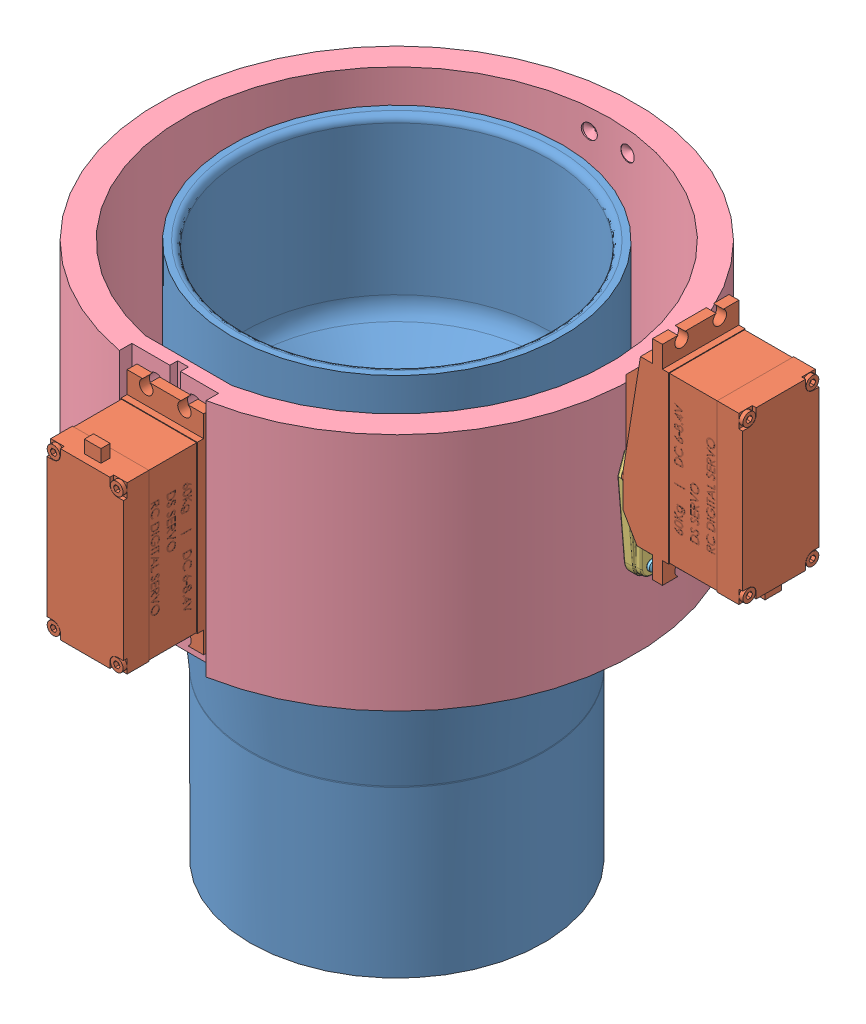
SolidWorks assembly Gimbal V7, configuration Default. Lengths in mm.
Overall size (244.08 241.79 215.67).
20 component instances, 8 part files, 37 mates.
Components (placement in the parent):
- Gimbal Nozzle - Rigid-1: Gimbal Nozzle - Rigid [Default] at origin size (130 210 130)
- Servo 1_Gimbal System_TVR_UBC Rocket-1: Servo 1_Gimbal System_TVR_UBC Rocket [Default] at (-231.9464 -144.8218 286.4196) x (0 1 0) z (0 0 -1) size (81.92 30 55.94)
  - Assem3^Servo 1_Gimbal System_TVR_UBC Rocket-1: Assem3^Servo 1_Gimbal System_TVR_UBC Rocket [Default] at origin (virtual)
  - 60Kg Servo-1: 60Kg Servo [Default] at (97.8618 231.9464 179.8846) x (-1 0 0) z (0 1 0) size (81.92 55.94 30)
- V4_Linkage_Gimbal System_TVR_UBC Rocket-1: V4_Linkage_Gimbal System_TVR_UBC Rocket [Default] at (0 -22.2131 65) x (0 -1 0) z (0 0 1) size (42.76 14.24 8)
- Servo 1_Gimbal System_TVR_UBC Rocket-2: Servo 1_Gimbal System_TVR_UBC Rocket [Default] at (314.8225 88.6957 -231.9464) x (0 -1 0) z (-1 0 0) size (81.92 30 55.94)
  - Assem3^Servo 1_Gimbal System_TVR_UBC Rocket-1: Assem3^Servo 1_Gimbal System_TVR_UBC Rocket [Default] at origin (virtual)
  - 60Kg Servo-1: 60Kg Servo [Default] at (97.8618 231.9464 179.8846) x (-1 0 0) z (0 1 0) size (81.92 55.94 30)
- Part2-1: Part2 [Default] at origin
- Part3-1: Part3 [Default] at origin
- Part4-1: Part4 [Default] x (1 0 0) z (0 1 0) size (186.81 185.25 93.92)
- V4_Linkage_Gimbal System_TVR_UBC Rocket-2: V4_Linkage_Gimbal System_TVR_UBC Rocket [Default] at (93.4029 -22.2131 0) x (0 -1 0) z (1 0 0) size (42.76 14.24 8)
- 95836A113_Black-Oxide 18-8 Stainless Steel Pan Head Phillips Screws-1: 95836A113_Black-Oxide 18-8 Stainless Steel Pan Head Phillips Screws [95836A113] at (0 -50.1169 67.33) size (4 4 11.88)
- 95836A113_Black-Oxide 18-8 Stainless Steel Pan Head Phillips Screws-2: 95836A113_Black-Oxide 18-8 Stainless Steel Pan Head Phillips Screws [95836A113] at (0 -60.1169 67.33) x (0.864816 0.502088 0) z (0 0 1) size (4 4 11.88)
- 94459A120_Heat-Set Inserts for Plastic-1: 94459A120_Heat-Set Inserts for Plastic [94459A120] at (0 -50.1169 63) x (-0.923728 -0.383049 0) z (-0.383049 0.923728 0) size (3.62 4.02 3.63)
- 94459A120_Heat-Set Inserts for Plastic-2: 94459A120_Heat-Set Inserts for Plastic [94459A120] at (0 -60.1169 63) x (-0.923835 -0.38279 0) z (-0.38279 0.923835 0) size (3.62 4.02 3.63)
- 94459A120_Heat-Set Inserts for Plastic-3: 94459A120_Heat-Set Inserts for Plastic [94459A120] at (91.4029 -50.1169 0) x (0 0.381849 -0.924225) z (0 -0.924225 -0.381849) size (3.62 4.02 3.63)
- 94459A120_Heat-Set Inserts for Plastic-4: 94459A120_Heat-Set Inserts for Plastic [94459A120] at (91.4029 -60.1169 0) x (0 0.381849 -0.924225) z (0 -0.924225 -0.381849) size (3.62 4.02 3.63)
- 95836A113_Black-Oxide 18-8 Stainless Steel Pan Head Phillips Screws-3: 95836A113_Black-Oxide 18-8 Stainless Steel Pan Head Phillips Screws [95836A113] at (95.7329 -60.1169 0) x (0 -0.924225 -0.381849) z (1 0 0) size (4 4 11.88)
- 95836A113_Black-Oxide 18-8 Stainless Steel Pan Head Phillips Screws-4: 95836A113_Black-Oxide 18-8 Stainless Steel Pan Head Phillips Screws [95836A113] at (95.7329 -50.1169 0) x (0 -0.924225 -0.381849) z (1 0 0) size (4 4 11.88)
Mates (geometry in assembly coordinates):
- Coincident3: coincident aligned: plane of Gimbal Nozzle - Rigid-1 through (0 0 0) normal (0 0 1)
- Coincident4: coincident aligned: plane of Gimbal Nozzle - Rigid-1 through (0 0 0) normal (0 1 0)
- Coincident5: coincident aligned: plane of Gimbal Nozzle - Rigid-1 through (0 0 0) normal (1 0 0)
- Coincident6: coincident aligned: plane of Servo 1_Gimbal System_TVR_UBC Rocket-2/60Kg Servo-1 through (134.9379 -9.1661 0) normal (0 0 1)
- Parallel1: parallel anti-aligned: plane of Servo 1_Gimbal System_TVR_UBC Rocket-2/60Kg Servo-1 through (134.9379 -9.1661 0) normal (-1 0 0)
- InPlace2: in place: plane of Part4-1 through (0 0 0) normal (0 1 0); moOrthogonalPlaneRef_w of Part4-1 through (0 0 0) normal (0 0 -1); plane of Part4-1 through (0 0 0) normal (1 0 0); unknown of Part4-1
- Coincident12: coincident aligned: 
- Coincident13: coincident aligned: plane of Part4-1 through (0 0 0) normal (0 0 -1)
- Coincident14: coincident anti-aligned: plane of Part4-1 through (0 0 0) normal (1 0 0)
- Coincident15: coincident aligned: plane of Servo 1_Gimbal System_TVR_UBC Rocket-1/60Kg Servo-1 through (0 -46.96 106.535) normal (1 0 0)
- Parallel2: parallel anti-aligned: plane of Gimbal Nozzle - Rigid-1 through (0 0 0) normal (0 0 1); plane of Servo 1_Gimbal System_TVR_UBC Rocket-1/60Kg Servo-1 through (0 -46.96 106.535) normal (0 0 -1)
- Distance3: distance = 6 mm aligned: plane of Servo 1_Gimbal System_TVR_UBC Rocket-1/60Kg Servo-1 through (15 -6 86.93) normal (0 1 0); plane of Part4-1 through (0 0 0) normal (0 1 0)
- Coincident23: coincident: plane of Servo 1_Gimbal System_TVR_UBC Rocket-1/60Kg Servo-1 through (0 -28.0631 106.535) normal (0 1 0); line of Servo 1_Gimbal System_TVR_UBC Rocket-2 through (98.4856 -28.0631 0) axis (-1 0 0)
- Concentric3: concentric anti-aligned: circle of Servo 1_Gimbal System_TVR_UBC Rocket-1/60Kg Servo-1; circle of V4_Linkage_Gimbal System_TVR_UBC Rocket-1
- Coincident24: coincident anti-aligned: plane of Servo 1_Gimbal System_TVR_UBC Rocket-1/60Kg Servo-1 through (0 -28.0631 67.5) normal (0 0 -1); plane of V4_Linkage_Gimbal System_TVR_UBC Rocket-1 through (0 -28.0631 67.5) normal (0 0 1)
- Parallel4: parallel aligned: plane of V4_Linkage_Gimbal System_TVR_UBC Rocket-1 through (0 -22.2131 65) normal (1 0 0)
- Tangent1: tangent anti-aligned: cylinder of Gimbal Nozzle - Rigid-1 through (0 0 0) axis (0 1 0) radius 65; plane of V4_Linkage_Gimbal System_TVR_UBC Rocket-1 through (0.5 -28.0631 65) normal (0 0 -1)
- Concentric4: concentric aligned: circle of Servo 1_Gimbal System_TVR_UBC Rocket-2/60Kg Servo-1; circle of V4_Linkage_Gimbal System_TVR_UBC Rocket-2
- Coincident25: coincident anti-aligned: plane of Servo 1_Gimbal System_TVR_UBC Rocket-2/60Kg Servo-1 through (95.9029 -28.0631 0) normal (-1 0 0); plane of V4_Linkage_Gimbal System_TVR_UBC Rocket-2 through (95.9029 -28.0631 0) normal (1 0 0)
- Perpendicular1: perpendicular: plane of V4_Linkage_Gimbal System_TVR_UBC Rocket-2 through (93.4029 -22.2131 0) normal (0 0 -1)
- Tangent2: tangent anti-aligned: cylinder of Part4-1 through (0 -364.1034 0) axis (0 1 0) radius 93.4029; plane of V4_Linkage_Gimbal System_TVR_UBC Rocket-2 through (93.4029 -28.0631 -0.5) normal (-1 0 0)
- Concentric5: concentric aligned: circle of V4_Linkage_Gimbal System_TVR_UBC Rocket-1; circle of 95836A113_Black-Oxide 18-8 Stainless Steel Pan Head Phillips Screws-1
- Coincident30: coincident anti-aligned: plane of V4_Linkage_Gimbal System_TVR_UBC Rocket-1 through (0 -28.0631 71.47) normal (0 0 1); plane of 95836A113_Black-Oxide 18-8 Stainless Steel Pan Head Phillips Screws-1 through (0 -49.0869 71.47) normal (0 0 -1)
- Concentric6: concentric aligned: circle of V4_Linkage_Gimbal System_TVR_UBC Rocket-1; circle of 95836A113_Black-Oxide 18-8 Stainless Steel Pan Head Phillips Screws-2
- Coincident31: coincident anti-aligned: plane of V4_Linkage_Gimbal System_TVR_UBC Rocket-1 through (0 -28.0631 71.47) normal (0 0 1); plane of 95836A113_Black-Oxide 18-8 Stainless Steel Pan Head Phillips Screws-2 through (-0.5172 -59.2261 71.47) normal (0 0 -1)
- Concentric10: concentric aligned: cylinder of Gimbal Nozzle - Rigid-1 through (0 -50.1169 65) axis (0 0 1) radius 1.5; circle of 94459A120_Heat-Set Inserts for Plastic-1
- Concentric11: concentric aligned: cylinder of Gimbal Nozzle - Rigid-1 through (0 -60.1169 65) axis (0 0 1) radius 1.5; circle of 94459A120_Heat-Set Inserts for Plastic-2
- Tangent5: tangent aligned: cylinder of Gimbal Nozzle - Rigid-1 through (0 0 0) axis (0 1 0) radius 65; plane of 94459A120_Heat-Set Inserts for Plastic-2 through (-1.6629 -60.8059 65) normal (0 0 1)
- Tangent6: tangent aligned: cylinder of Gimbal Nozzle - Rigid-1 through (0 0 0) axis (0 1 0) radius 65; plane of 94459A120_Heat-Set Inserts for Plastic-1 through (-1.6627 -50.8064 65) normal (0 0 1)
- Concentric12: concentric aligned: cylinder of Part4-1 through (93.4029 -50.1169 0) axis (1 0 0) radius 1.5; circle of 94459A120_Heat-Set Inserts for Plastic-3
- Tangent7: tangent aligned: cylinder of Part4-1 through (0 -364.1034 0) axis (0 1 0) radius 93.4029; plane of 94459A120_Heat-Set Inserts for Plastic-3 through (93.4029 -49.4296 -1.6636) normal (1 0 0)
- Concentric13: concentric aligned: cylinder of Part4-1 through (93.4029 -60.1169 0) axis (1 0 0) radius 1.5; circle of 94459A120_Heat-Set Inserts for Plastic-4
- Tangent8: tangent aligned: cylinder of Part4-1 through (0 -364.1034 0) axis (0 1 0) radius 93.4029; plane of 94459A120_Heat-Set Inserts for Plastic-4 through (93.4029 -59.4296 -1.6636) normal (1 0 0)
- Concentric14: concentric aligned: circle of V4_Linkage_Gimbal System_TVR_UBC Rocket-2; circle of 95836A113_Black-Oxide 18-8 Stainless Steel Pan Head Phillips Screws-3
- Coincident32: coincident anti-aligned: plane of V4_Linkage_Gimbal System_TVR_UBC Rocket-2 through (99.8729 -28.0631 0) normal (1 0 0); plane of 95836A113_Black-Oxide 18-8 Stainless Steel Pan Head Phillips Screws-3 through (99.8729 -59.7236 -0.952) normal (-1 0 0)
- Concentric15: concentric: cylinder of V4_Linkage_Gimbal System_TVR_UBC Rocket-2 through (99.8729 -50.1169 0) axis (1 0 0) radius 1.25; circle of 95836A113_Black-Oxide 18-8 Stainless Steel Pan Head Phillips Screws-4
- Coincident33: coincident anti-aligned: plane of V4_Linkage_Gimbal System_TVR_UBC Rocket-2 through (99.8729 -28.0631 0) normal (1 0 0); plane of 95836A113_Black-Oxide 18-8 Stainless Steel Pan Head Phillips Screws-4 through (99.8729 -49.7236 -0.952) normal (-1 0 0)
